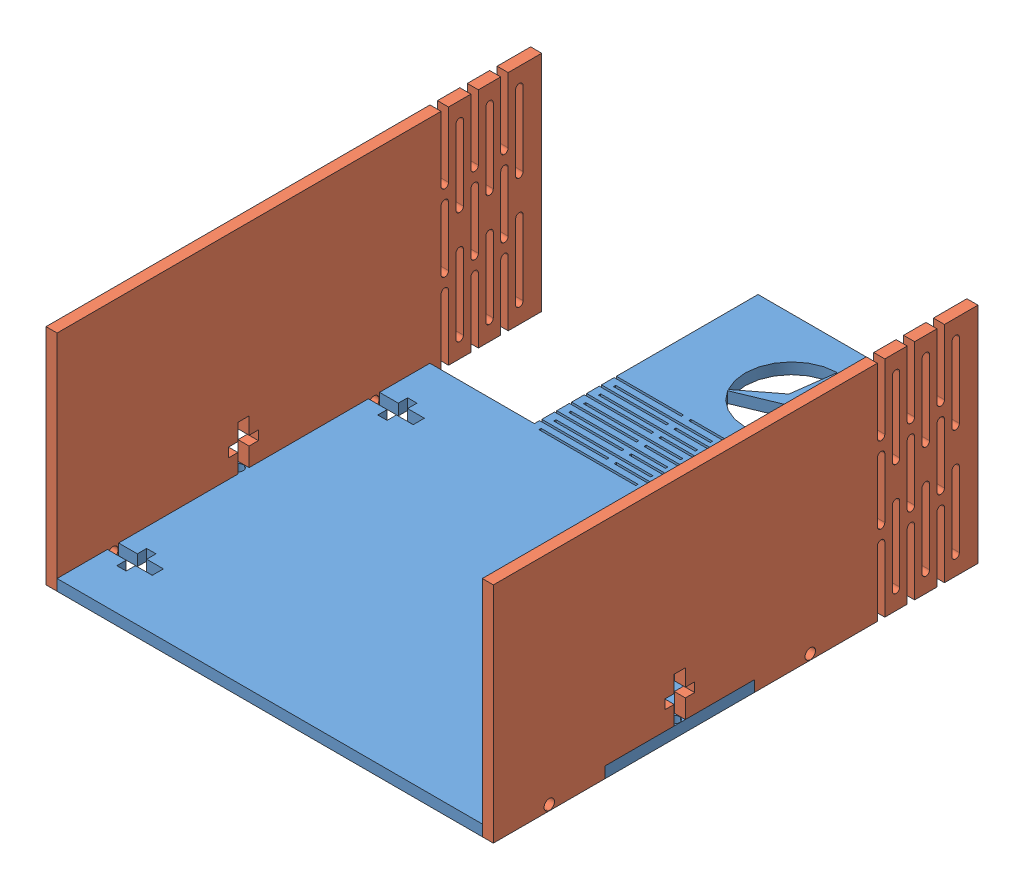
SolidWorks assembly 装配体1, configuration Default. Lengths in mm.
Overall size (120 60 160).
3 component instances, 2 part files, 6 mates.
Components (placement in the parent):
- plate1-1: plate1 [Default] at (-5.7143 97.3806 146.9025) size (120 2.97 160)
- plate2-1: plate2 [Default] at (-62.7425 127.3806 176.9025) x (0 1 0) z (0 0 1) size (60 2.97 130)
- plate2-2: plate2 [Default] at (54.2857 127.3806 176.9025) x (0 1 0) z (0 0 1) size (60 2.97 130)
Mates (geometry in assembly coordinates):
- 重合1: coincident: plane of plate1-1 through (-5.7143 97.3806 146.9025) normal (0 -1 0); plane of plate2-1 through (-65.7143 97.3806 176.9025) normal (0 -1 0)
- 重合2: coincident: plane of plate1-1 through (-62.7425 90.3524 226.9025) normal (-1 0 0); plane of plate2-1 through (-62.7425 127.3806 176.9025) normal (1 0 0)
- 重合3: coincident: plane of plate1-1 through (-5.7143 100.3524 226.9025) normal (0 0 1); plane of plate2-1 through (-65.7143 127.3806 226.9025) normal (0 0 1)
- 重合4: coincident: plane of plate1-1 through (51.3139 90.3524 126.9025) normal (1 0 0); plane of plate2-2 through (51.3139 127.3806 176.9025) normal (-1 0 0)
- 重合5: coincident: plane of plate1-1 through (-5.7143 97.3806 146.9025) normal (0 -1 0); plane of plate2-2 through (51.3139 97.3806 176.9025) normal (0 -1 0)
- 重合6: coincident: plane of plate1-1 through (-5.7143 100.3524 226.9025) normal (0 0 1); line of plate2-2 through (54.2857 157.3806 226.9025) axis (0 -1 0)
